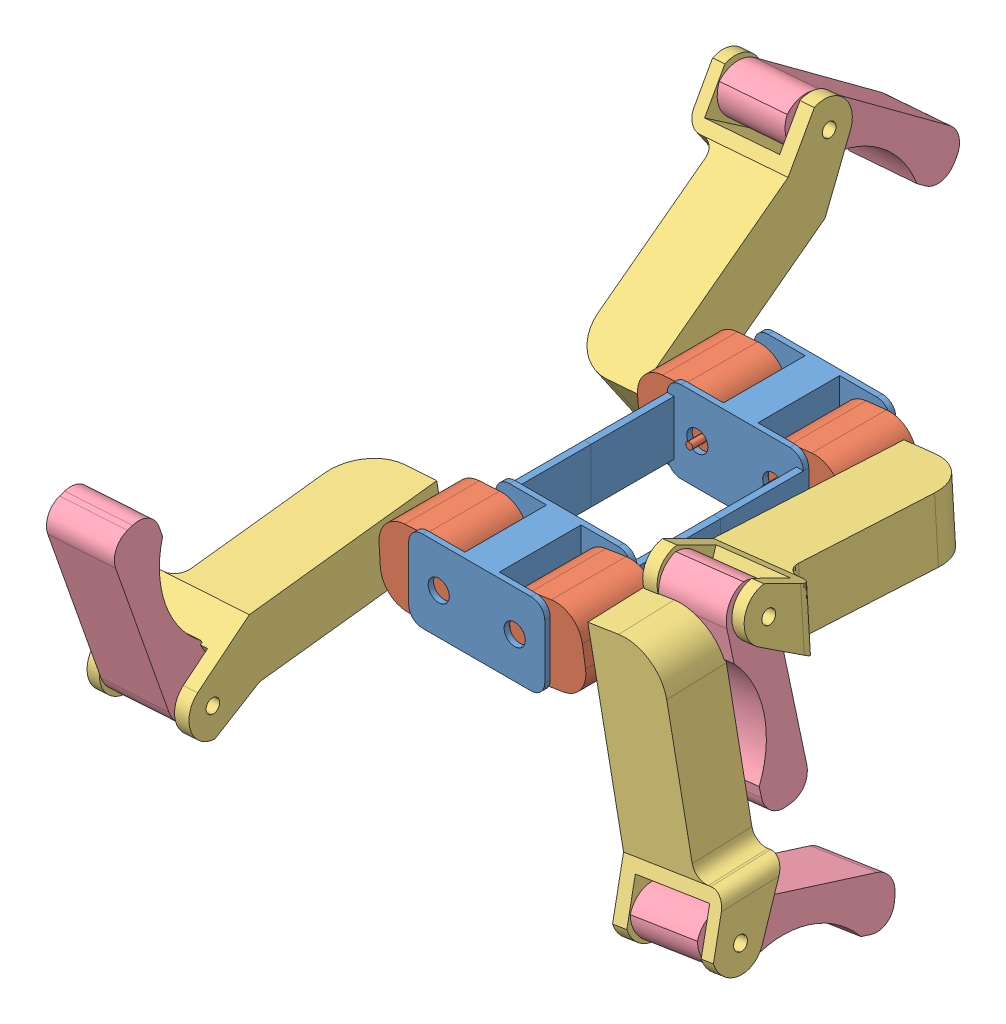
SolidWorks assembly assembl, configuration По умолчанию. Lengths in mm.
Overall size (336.3 318.59 628.61).
14 component instances, 4 part files, 28 mates.
Components (placement in the parent):
- 1-1: 1 [По умолчанию] at origin size (100 60 129)
- 1-3: 1 [По умолчанию] at (-100 0 -122) x (-1 0 0) z (0 0 -1) size (100 60 129)
- 2-1: 2 [По умолчанию] at (-70.7199 35.5032 24.9761) x (0 0 -1) z (-0.998022 -0.062863 0) size (65 55 65)
- 2-2: 2 [По умолчанию] at (-70.0201 25.5582 -141.9761) x (0 0 1) z (-0.996991 -0.077515 0) size (65 55 65)
- 3-1: 3 [По умолчанию] at (-125.8168 35.3109 98.9358) x (-0.062477 0.991886 0.110716) z (-0.998022 -0.062863 0) size (59.05 191.3 75)
- 4-1: 4 [По умолчанию] at (-141.6291 32.9858 204.5729) x (-0.01865 0.296087 -0.954979) z (-0.060033 0.95309 0.296674) size (33.97 60 144.36)
- 3-2: 3 [По умолчанию] at (-126.8793 47.3355 -212.8547) x (0.064645 -0.831459 -0.551812) z (-0.996991 -0.077515 0) size (59.05 191.3 75)
- 4-2: 4 [По умолчанию] at (-147.0362 101.1202 -310.5291) x (0.062744 -0.807008 0.587197) z (0.045516 -0.585431 -0.809444) size (33.97 60 144.36)
- 2-3: 2 [По умолчанию] at (-28.7386 23.8534 24.9761) x (0 0 -1) z (0.987886 0.155178 0) size (65 55 65)
- 3-3: 3 [По умолчанию] at (34.2157 -22.4913 19.2996) x (-0.005167 0.032891 -0.999446) z (0.987886 0.155178 0) size (59.05 191.3 75)
- 4-3: 4 [По умолчанию] at (110.1234 -115.0642 5.0947) x (0.149141 -0.949451 0.276224) z (0.042864 -0.272878 -0.961093) size (33.97 60 144.36)
- 3-4: 3 [По умолчанию] at (26.4695 23.22 -91.7141) x (0.11321 -0.992425 0.047705) z (0.993556 0.113339 0) size (59.05 191.3 75)
- 4-4: 4 [По умолчанию] at (87.4547 23.4896 -8.1012) x (0.013561 -0.118875 0.992817) z (0.112525 -0.986419 -0.119646) size (33.97 60 144.36)
- 2-6: 2 [По умолчанию] at (-30.1346 34.155 -141.9761) x (0 0 1) z (0.993556 0.113339 0) size (65 55 65)
Mates (geometry in assembly coordinates):
- Параллельность1: parallel anti-aligned: plane of 1-1 through (0 0 -61) normal (0 0 -1); plane of 1-3 through (-100 0 -61) normal (0 0 1)
- Совпадение4: coincident anti-aligned: plane of 1-1 through (0 0 -61) normal (0 0 -1); plane of 1-3 through (-100 0 -61) normal (0 0 1)
- Концентричный1: concentric anti-aligned: cylinder of 1-1 through (-77.9118 30 90.105) axis (0 0 -1) radius 7.8153; cylinder of 1-3 through (-77.9118 30 -212.105) axis (0 0 1) radius 7.8153
- Концентричный2: concentric anti-aligned: cylinder of 1-1 through (-22.0882 30 90.105) axis (0 0 -1) radius 7.8153; cylinder of 1-3 through (-22.0882 30 -212.105) axis (0 0 1) radius 7.8153
- Концентричный3: concentric anti-aligned: cylinder of 1-1 through (-77.9118 30 90.105) axis (0 0 -1) radius 7.8153; cylinder of 2-1 through (-77.9118 30 -1) axis (0 0 1) radius 2.5
- Совпадение5: coincident anti-aligned: plane of 1-1 through (-111.8917 -77.6024 64) normal (0 0 -1); plane of 2-1 through (-123.5655 -0.4301 64) normal (0 0 1)
- Концентричный4: concentric anti-aligned: cylinder of 1-3 through (-77.9118 30 -212.105) axis (0 0 1) radius 7.8153; cylinder of 2-2 through (-77.9118 30 -116) axis (0 0 -1) radius 2.5
- Совпадение6: coincident anti-aligned: plane of 1-3 through (-111.8917 -77.6024 -126) normal (0 0 -1); plane of 2-2 through (-127.377 53.7371 -126) normal (0 0 1)
- Концентричный5: concentric aligned: cylinder of 2-1 through (-135.2745 26.3868 36.5) axis (0.998022 0.062863 0) radius 2.5; cylinder of 3-1 through (-135.2745 26.3868 36.5) axis (0.998022 0.062863 0) radius 5
- Совпадение7: coincident anti-aligned: plane of 2-1 through (-135.2745 26.3868 36.5) normal (-0.998022 -0.062863 0); plane of 3-1 through (-135.2745 26.3868 36.5) normal (0.998022 0.062863 0)
- Концентричный6: concentric anti-aligned: cylinder of 3-1 through (-109.1132 -4.9093 188.6251) axis (-0.998022 -0.062863 0) radius 5; cylinder of 4-1 through (-199.0044 -10.5714 188.6251) axis (0.998022 0.062863 0) radius 2.5
- Совпадение8: coincident anti-aligned: plane of 3-1 through (-191.7303 33.0186 189.1395) normal (0.998022 0.062863 0); plane of 4-1 through (-194.2601 73.182 139.0748) normal (-0.998022 -0.062863 0)
- Концентричный7: concentric aligned: cylinder of 2-2 through (-135.2152 25.5447 -153.5) axis (0.996991 0.077515 0) radius 2.5; cylinder of 3-2 through (-135.2152 25.5447 -153.5) axis (0.996991 0.077515 0) radius 5
- Совпадение9: coincident anti-aligned: plane of 2-2 through (-135.2152 25.5447 -153.5) normal (-0.996991 -0.077515 0); plane of 3-2 through (-135.2152 25.5447 -153.5) normal (0.996991 0.077515 0)
- Концентричный8: concentric anti-aligned: line of 3-2 through (-198.6204 119.555 -273.886) axis (-0.996991 -0.077515 0); cylinder of 4-2 through (-208.5903 118.7798 -273.886) axis (0.996991 0.077515 0) radius 2.5
- Совпадение10: coincident anti-aligned: plane of 3-2 through (-195.6691 81.5955 -293.9767) normal (0.996991 0.077515 0); plane of 4-2 through (-191.1497 23.4677 -284.0744) normal (-0.996991 -0.077515 0)
- Концентричный9: concentric anti-aligned: cylinder of 1-1 through (-22.0882 30 90.105) axis (0 0 -1) radius 7.8153; cylinder of 2-3 through (-22.0882 30 -1) axis (0 0 1) radius 2.5
- Совпадение11: coincident anti-aligned: plane of 2-3 through (20.5457 64.5342 64) normal (0 0 1); plane of 1-1 through (11.8917 -77.6024 64) normal (0 0 -1)
- Концентричный10: concentric aligned: cylinder of 2-3 through (34.6919 38.9191 36.5) axis (-0.987886 -0.155178 0) radius 2.5; cylinder of 3-3 through (34.6919 38.9191 36.5) axis (-0.987886 -0.155178 0) radius 5
- Совпадение12: coincident anti-aligned: plane of 2-3 through (34.6919 38.9191 36.5) normal (0.987886 0.155178 0); plane of 3-3 through (34.6919 38.9191 36.5) normal (-0.987886 -0.155178 0)
- Концентричный11: concentric aligned: line of 3-3 through (48.9078 -116.0232 47.1702) axis (0.987886 0.155178 0); cylinder of 4-3 through (49.5231 -115.9266 47.1702) axis (0.987886 0.155178 0) radius 2.5
- Совпадение13: coincident anti-aligned: plane of 3-3 through (58.5208 -108.7649 4.4968) normal (0.987886 0.155178 0); plane of 4-3 through (72.9238 -200.4564 4.7497) normal (-0.987886 -0.155178 0)
- Концентричный14: concentric anti-aligned: cylinder of 1-3 through (-22.0882 30 -212.105) axis (0 0 1) radius 7.8153; cylinder of 2-6 through (-22.0882 30 -116) axis (0 0 -1) radius 2.5
- Совпадение14: coincident anti-aligned: plane of 1-3 through (11.8917 -77.6024 -126) normal (0 0 -1); plane of 2-6 through (28.1991 8.0582 -126) normal (0 0 1)
- Концентричный15: concentric aligned: cylinder of 3-4 through (35.0178 36.5143 -153.5) axis (-0.993556 -0.113339 0) radius 5; cylinder of 2-6 through (35.0178 36.5143 -153.5) axis (-0.993556 -0.113339 0) radius 2.5
- Совпадение15: coincident anti-aligned: plane of 3-4 through (35.0178 36.5143 -153.5) normal (-0.993556 -0.113339 0); plane of 2-6 through (35.0178 36.5143 -153.5) normal (0.993556 0.113339 0)
- Концентричный16: concentric aligned: cylinder of 3-4 through (8.4015 56.8307 0.3984) axis (0.993556 0.113339 0) radius 5; cylinder of 4-4 through (23.0714 58.5042 0.3984) axis (0.993556 0.113339 0) radius 2.5
- Совпадение16: coincident anti-aligned: plane of 3-4 through (37.8797 16.9216 -1.8078) normal (0.993556 0.113339 0); plane of 4-4 through (41.2798 -12.8838 64.1526) normal (-0.993556 -0.113339 0)
